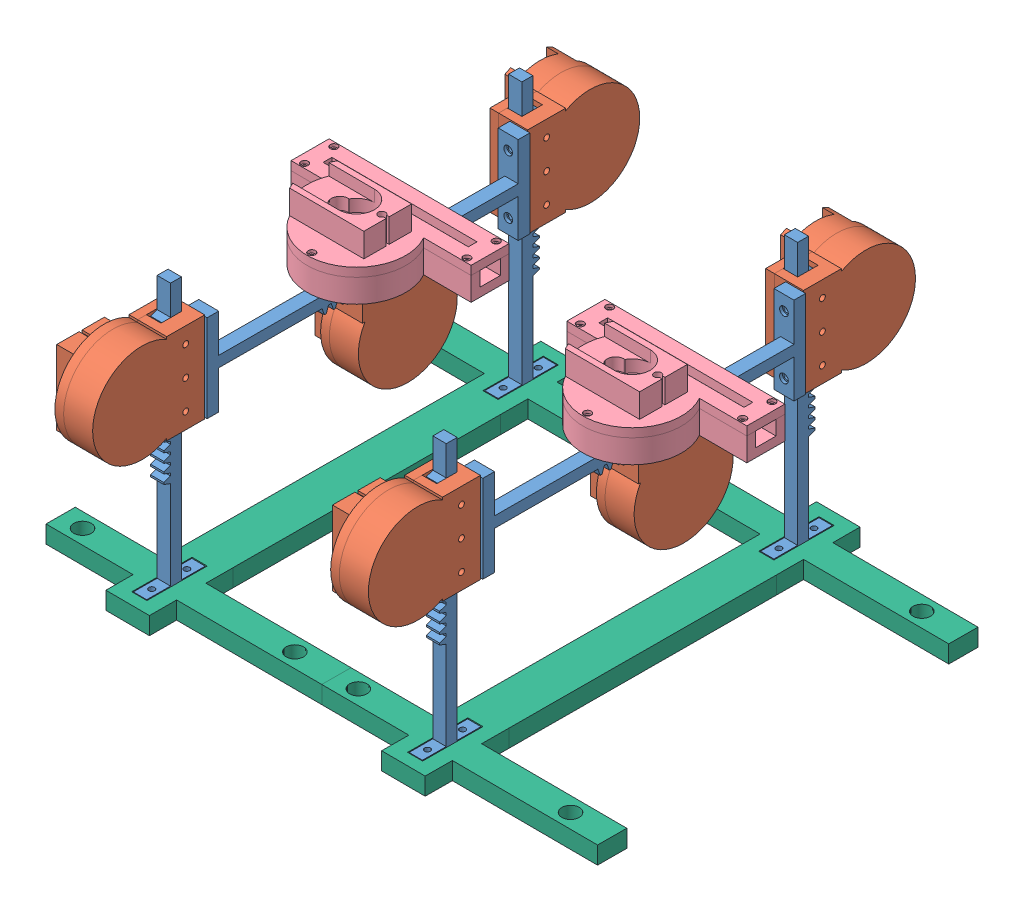
SolidWorks assembly Assem2, configuration Default. Lengths in mm.
Overall size (190.61 97.31 187.39).
20 component instances, 6 part files, 29 mates.
Components (placement in the parent):
- Part3-10: Part3 [v2] at (35.5879 91.4589 -7.6431) x (0 1 0) z (-0.004123 0 0.999991) size (94 4.6 20)
- Part1_v2-5: Part1_v2 [Default] at (35.6595 103.0369 -24.9911) x (0 1 0) z (0.004123 0 -0.999991) size (33.8 21.2 38.3)
- Part1_v2-6: Part1_v2 [Default] at (35.0281 103.0369 128.1235) x (0 -1 0) z (-0.004123 0 0.999991) size (33.8 21.2 38.3)
- Part3-13: Part3 [v2] at (30.4997 91.4589 110.7565) x (0 1 0) z (0.004123 0 -0.999991) size (94 4.6 20)
- Part1_v2-7: Part1_v2 [Default] at (41.1675 86.4993 43.1035) x (0.004123 0 -0.999991) z (0 -1 0) size (33.8 21.2 38.3)
- Cross_connector-1: Cross_connector [Default] at (43.5062 107.8971 43.1132) x (0.004123 0 -0.999991) z (0.999991 0 0.004123) size (30 3 30)
- Part1-4: Part1 [Default] at (43.4447 113.8971 58.0108) x (-0.999991 0 -0.004123) z (-0.004123 0 0.999991) size (62 19.2 38.3)
- Part2-2: Part2 [Default] at (40.6685 83.1722 42.857) x (-0.004096 0.115597 0.993288) z (-0.000477 -0.993296 0.115596) size (26.96 7.5 26.97)
- Part3-14: Part3 [v2_hhor] at (36.5676 103.0369 43.0712) x (0 1 0) z (0.004123 0 -0.999991) size (30 6.9 110.32)
- Base-4: Base [reference_base] at (-20.4845 34.7838 44.2265) x (-0.999991 0 -0.004123) z (0.004123 0 -0.999991) size (95 6 148.6)
- Part1_v2-8: Part1_v2 [Default] at (136.1667 86.4993 43.4953) x (0.004123 0 -0.999991) z (0 -1 0) size (33.8 21.2 38.3)
- Part3-16: Part3 [v2] at (125.4989 91.4589 111.1483) x (0 1 0) z (0.004123 0 -0.999991) size (94 4.6 20)
- Part1_v2-9: Part1_v2 [Default] at (130.6587 103.0369 -24.5994) x (0 1 0) z (0.004123 0 -0.999991) size (33.8 21.2 38.3)
- Part1_v2-10: Part1_v2 [Default] at (130.0273 103.0369 128.5152) x (0 -1 0) z (-0.004123 0 0.999991) size (33.8 21.2 38.3)
- Part3-17: Part3 [v2] at (130.5871 91.4589 -7.2514) x (0 1 0) z (-0.004123 0 0.999991) size (94 4.6 20)
- Part1-5: Part1 [Default] at (138.4439 113.8971 58.4025) x (-0.999991 0 -0.004123) z (-0.004123 0 0.999991) size (62 19.2 38.3)
- Part2-3: Part2 [Default] at (135.6677 83.1722 43.2487) x (-0.004096 0.115597 0.993288) z (-0.000477 -0.993296 0.115596) size (26.96 7.5 26.97)
- Part3-18: Part3 [v2_hhor] at (131.5668 103.0369 43.4629) x (0 1 0) z (0.004123 0 -0.999991) size (30 6.9 110.32)
- Base-7: Base [reference_base] at (74.5147 34.7838 44.6182) x (-0.999991 0 -0.004123) z (0.004123 0 -0.999991) size (95 6 148.6)
- Cross_connector-2: Cross_connector [Default] at (138.5054 107.8971 43.5049) x (0.004123 0 -0.999991) z (0.999991 0 0.004123) size (30 3 30)
Mates (geometry in assembly coordinates):
- Coincident44: coincident anti-aligned: plane of Part3-10 through (30.9837 68.7838 -6.6125) normal (-0.004123 0 0.999991); plane of Part1_v2-5 through (30.5837 103.0369 -6.6141) normal (0.004123 0 -0.999991)
- Coincident46: coincident anti-aligned: plane of Part3-10 through (35.5879 91.4589 -7.6431) normal (0.999991 0 0.004123); plane of Part1_v2-5 through (35.6595 103.0369 -24.9911) normal (-0.999991 0 -0.004123)
- Coincident47: coincident anti-aligned: plane of Part3-10 through (30.9837 68.7838 -6.6125) normal (-0.004123 0 0.999991); plane of Part1_v2-5 through (30.5837 103.0369 -6.6141) normal (0.004123 0 -0.999991)
- Concentric6: concentric aligned: circle of Part1_v2-5; circle of ?
- Concentric7: concentric aligned: circle of Part1_v2-5; circle of ?
- Coincident50: coincident anti-aligned: plane of Part1_v2-5 through (30.5713 99.6562 -3.6142) normal (-0.004123 0 0.999991); plane of ? through (39.0599 99.6562 -3.5792) normal (0.004123 0 -0.999991)
- Coincident51: coincident anti-aligned: circle of ?; circle of Part1_v2-6
- Coincident52: coincident anti-aligned: circle of ?; circle of Part1_v2-6
- Coincident53: coincident aligned: plane of Part3-10 through (35.5879 34.7838 -7.6431) normal (0 -1 0); plane of Part3-13 through (30.4997 34.7838 110.7565) normal (0 -1 0)
- Coincident54: coincident anti-aligned: plane of Part1_v2-6 through (35.0281 103.0369 128.1235) normal (-0.999991 0 -0.004123); plane of Part3-13 through (35.0997 91.4589 110.7755) normal (0.999991 0 0.004123)
- Coincident55: coincident anti-aligned: plane of Part1_v2-6 through (30.104 103.0369 109.7053) normal (-0.004123 0 0.999991); plane of Part3-13 through (35.104 68.7838 109.7259) normal (0.004123 0 -0.999991)
- Coincident56: coincident anti-aligned: plane of ? through (38.8661 123.3584 43.4204) normal (0.999991 0 0.004123); plane of Part1_v2-7 through (38.77 106.8208 66.7318) normal (-0.999991 0 -0.004123)
- Coincident57: coincident anti-aligned: plane of ? through (34.2662 125.2186 43.4015) normal (0 1 0); plane of Part1_v2-7 through (33.7701 125.2186 66.7112) normal (0 -1 0)
- Coincident58: coincident aligned: circle of Part1_v2-7; circle of Cross_connector-1
- Coincident59: coincident aligned: circle of Part1_v2-7; circle of Cross_connector-1
- Coincident60: coincident anti-aligned: circle of Cross_connector-1; circle of Part1-4
- Coincident61: coincident anti-aligned: circle of Cross_connector-1; circle of Part1-4
- Coincident62: coincident anti-aligned: plane of Part1_v2-7 through (39.1675 86.4993 43.0953) normal (-0.999991 0 -0.004123); plane of Part2-2 through (39.1675 86.4993 43.0953) normal (0.999991 0 0.004123)
- Concentric8: concentric aligned: circle of Part1_v2-7; circle of Part2-2
- RackPinionMate1: rack pinion = 26 mm: line of ? through (34.0903 125.2038 86.0613) axis (0.004123 0 -0.999991); circle of Part2-2
- Coincident64: coincident anti-aligned: circle of Part1_v2-5; circle of Part3-14
- Coincident65: coincident anti-aligned: cylinder of Part1_v2-5 through (37.9223 113.0369 -6.5839) axis (-0.004123 0 0.999991) radius 1; circle of Part3-14
- Coincident66: coincident anti-aligned: circle of Part1_v2-6; circle of Part3-14
- Coincident67: coincident anti-aligned: plane of Part1_v2-7 through (41.1675 86.4993 43.1035) normal (-0.999991 0 -0.004123); plane of Part3-14 through (41.1675 103.0369 43.0901) normal (0.999991 0 0.004123)
- Coincident68: coincident anti-aligned: plane of Part1_v2-7 through (36.1675 104.8971 43.0829) normal (0 -1 0); plane of Part3-14 through (41.1675 104.8971 43.0901) normal (0 1 0)
- Coincident87: coincident anti-aligned: circle of Part3-10; circle of Base-4
- Coincident88: coincident anti-aligned: circle of Part3-10; cylinder of Base-4 through (33.3161 32.7838 -14.4779) axis (0 1 0) radius 1
- Coincident89: coincident aligned: line of Base-4 through (90.7703 38.7838 -3.2409) axis (0.004123 0 -0.999991); line of ? through (90.7703 38.7838 -3.2409) axis (0.004123 0 -0.999991)
- Coincident90: coincident anti-aligned: line of Base-4 through (40.2759 38.7838 116.5519) axis (0.999991 0 0.004123); line of ? through (120.2745 38.7838 116.8817) axis (-0.999991 0 -0.004123)
